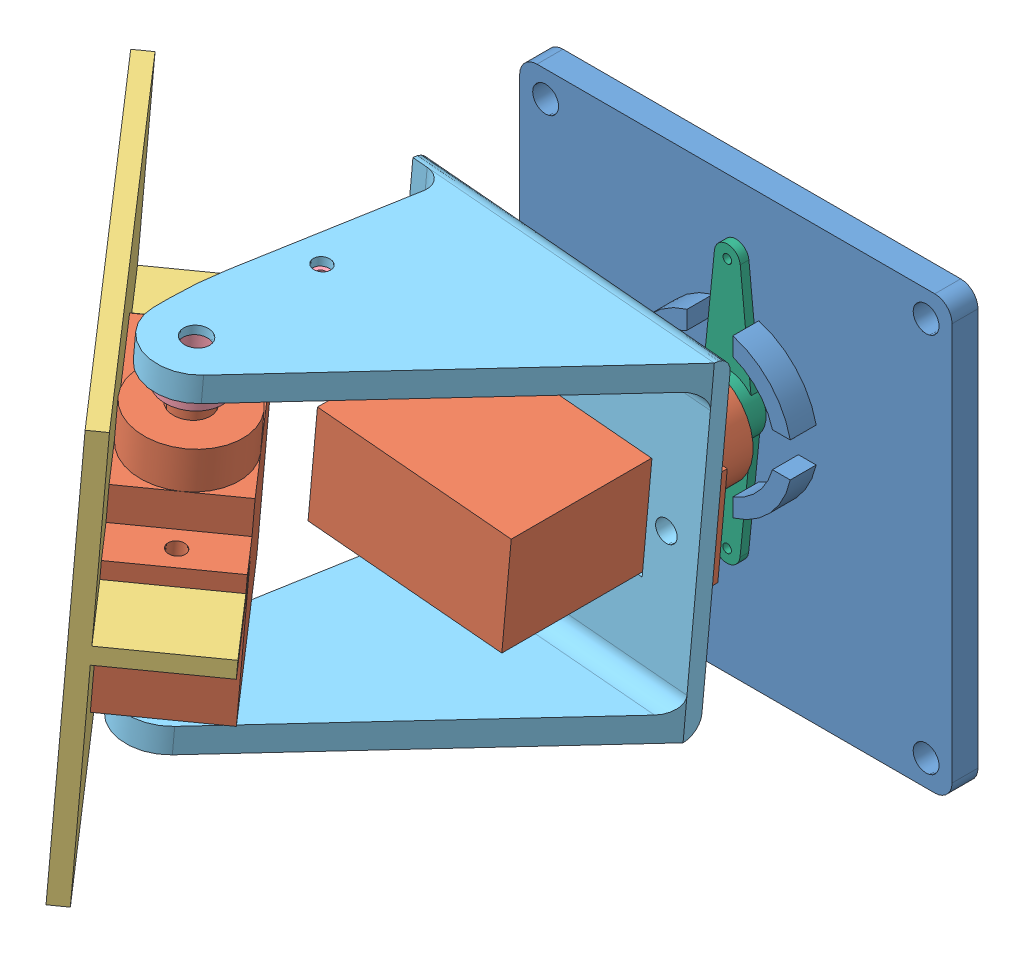
SolidWorks assembly 云台装配体, configuration 默认. Lengths in mm.
Overall size (70.66 56.84 69.67).
7 component instances, 6 part files, 15 mates.
Components (placement in the parent):
- 云台底座-1: 云台底座 [默认] at origin size (50 50 6)
- 9g小舵机-1: 9g小舵机 [默认] at (-22.4976 -10.5206 45.5276) x (0.651144 -0.059134 0.756647) z (0.090444 0.995902 0) size (32.5 12 32.5)
- 上板-1: 上板 [默认] at (-27.1241 5.4633 50.7582) x (0.651144 -0.059134 0.756647) z (0.753546 -0.068434 -0.653824) size (50 50 14)
- 9g小舵机-2: 9g小舵机 [默认] at (-5.2285 3.4748 35.5) x (0.995902 -0.090444 0) z (0 0 -1) size (32.5 12 32.5)
- 舵机柄-1: 舵机柄 [默认] at (-15.9588 23.5275 49.5) x (0 0 -1) z (-0.090444 -0.995902 0) size (19.5 7 4)
- 托架-1: 托架 [默认] at (-5.2285 3.4748 17.5) x (-0.090444 -0.995902 0) z (0 0 1) size (40 35 37)
- 舵机长柄-1: 舵机长柄 [默认] at (0 3 3) x (-0.00106 -0.999999 0) z (0 0 1) size (32 7 4)
Mates (geometry in assembly coordinates):
- 重合1: coincident anti-aligned: plane of 9g小舵机-1 through (-32.7163 8.4815 40.9383) normal (-0.753546 0.068434 0.653824); plane of 上板-1 through (-25.617 5.3264 49.4505) normal (0.753546 -0.068434 -0.653824)
- 重合2: coincident anti-aligned: circle of 9g小舵机-1; circle of 上板-1
- 重合4: coincident anti-aligned: plane of 云台底座-1 through (-23 -23 3) normal (0 0 1); plane of 9g小舵机-2 through (0 3 3) normal (0 0 -1)
- 同心1: concentric aligned: cylinder of 云台底座-1 through (0 3 0) axis (0 0 1) radius 1.25; cylinder of 9g小舵机-2 through (0 3 3) axis (0 0 1) radius 2.25
- 同心2: concentric anti-aligned: cylinder of 9g小舵机-1 through (-16.1397 21.5357 49.5) axis (-0.090444 -0.995902 0) radius 2.25; cylinder of 舵机柄-1 through (-16.0493 22.5316 49.5) axis (0.090444 0.995902 0) radius 2
- 距离1: distance = 2 mm aligned: plane of 舵机柄-1 through (-15.9588 23.5275 49.5) normal (0.090444 0.995902 0); plane of 9g小舵机-1 through (-16.1397 21.5357 49.5) normal (0.090444 0.995902 0)
- 同心3: concentric anti-aligned: circle of 9g小舵机-2; circle of 托架-1
- 同心4: concentric anti-aligned: circle of 9g小舵机-2; circle of 托架-1
- 重合7: coincident anti-aligned: plane of 9g小舵机-2 through (-5.2285 3.4748 17.5) normal (0 0 1); plane of 托架-1 through (-5.2285 3.4748 17.5) normal (0 0 -1)
- 同心7: concentric anti-aligned: cylinder of 9g小舵机-2 through (0 3 3) axis (0 0 1) radius 2.25; cylinder of 舵机长柄-1 through (0 3 4) axis (0 0 -1) radius 3.5
- 重合9: coincident anti-aligned: plane of 云台底座-1 through (-23 -23 3) normal (0 0 1); plane of 舵机长柄-1 through (0 3 3) normal (0 0 -1)
- 同心8: concentric anti-aligned: cylinder of 舵机柄-1 through (-16.0493 22.5316 49.5) axis (0.090444 0.995902 0) radius 3.5; cylinder of 托架-1 through (-15.0544 33.4865 49.5) axis (-0.090444 -0.995902 0) radius 1.5
- 同心9: concentric anti-aligned: cylinder of 舵机柄-1 through (-16.0493 22.5316 35) axis (0.090444 0.995902 0) radius 0.5; cylinder of 托架-1 through (-15.0544 33.4865 35) axis (-0.090444 -0.995902 0) radius 1
- 重合10: coincident anti-aligned: plane of 舵机柄-1 through (-15.9588 23.5275 49.5) normal (0.090444 0.995902 0); plane of 托架-1 through (-3.5101 22.397 17.5) normal (-0.090444 -0.995902 0)
- 平行1: parallel aligned: plane of 云台底座-1 through (-23 25 3) normal (0 1 0); plane of 托架-1
